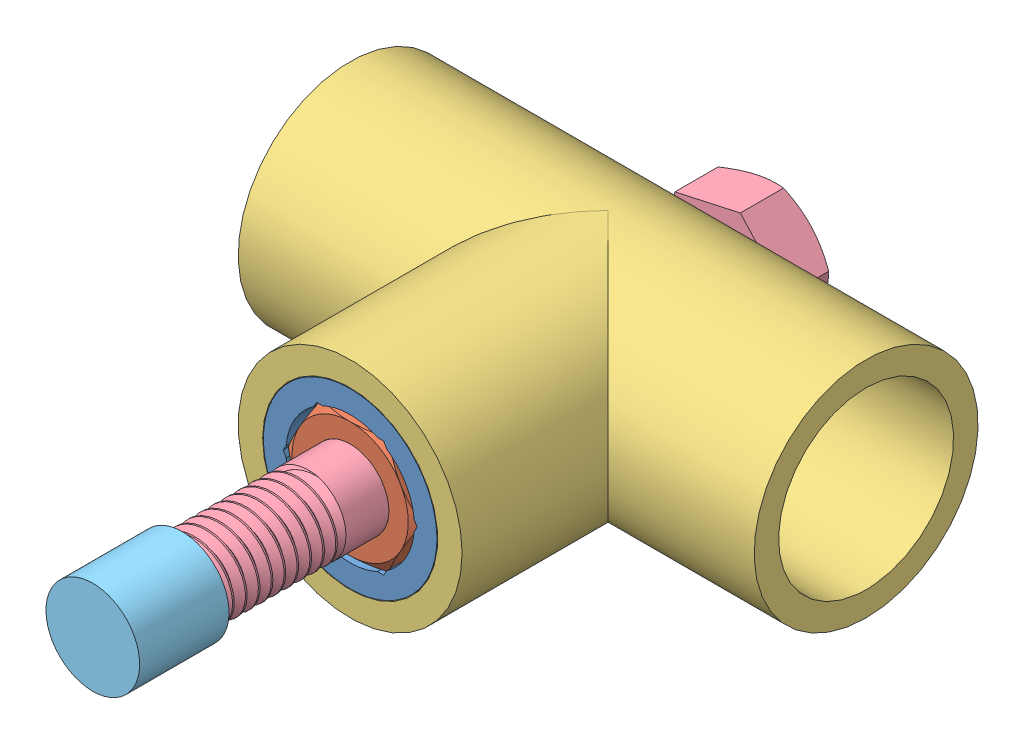
SolidWorks assembly BOLT, configuration Default. Lengths in mm.
Overall size (63.5 27.56 83.15).
5 component instances, 5 part files, 9 mates.
Components (placement in the parent):
- 1-2 PVC PIPE 1CM-1: 1-2 PVC PIPE 1CM [48925K91] at (8.3282 6.912 19.0537) size (21.34 21.34 10)
- 3-8 NUT-1: 3-8 NUT [94804A320] at (8.3282 6.912 19.8865) x (-0.866025 0.5 0) z (0 0 1) size (14.29 16.5 10.6)
- BOLT TEE-1: BOLT TEE [4880K41] at (8.3282 6.912 -7.6963) x (1 0 0) z (0 -1 0) size (63.5 45.53 27.56)
- 3-8 HEX HEAD CAP SCREW-1: 3-8 HEX HEAD CAP SCREW [92186A636] at (8.3282 6.912 13.6476) x (0 0 1) z (-0.95338 0.301772 0) size (82.75 16.5 14.29)
- VELCRO E-1: VELCRO E [Default] at (8.3282 6.912 55.7242) x (1 0 0) z (0 1 0) size (11.53 11 11.53)
Mates (geometry in assembly coordinates):
- Coincident1: coincident anti-aligned: plane of 1-2 PVC PIPE 1CM-1 through (0.0793 6.912 14.0537) normal (0.866025 0.5 0); plane of 3-8 NUT-1 through (0.0793 6.912 24.0537) normal (-0.866025 -0.5 0)
- Concentric1: concentric aligned: circle of 1-2 PVC PIPE 1CM-1; circle of 3-8 NUT-1
- Coincident2: coincident aligned: plane of 1-2 PVC PIPE 1CM-1 through (8.3282 6.912 24.0537) normal (0 0 1); plane of 3-8 NUT-1 through (12.4526 -0.2318 24.0537) normal (0 0 1)
- Concentric2: concentric aligned: cylinder of 1-2 PVC PIPE 1CM-1 through (8.3282 6.912 24.0537) axis (0 0 -1) radius 10.668; cone of BOLT TEE-1 through (8.3282 6.912 24.0537) axis (0 0 -1)
- Coincident3: coincident aligned: plane of 1-2 PVC PIPE 1CM-1 through (8.3282 6.912 24.0537) normal (0 0 1); plane of BOLT TEE-1 through (22.1077 6.912 24.0537) normal (0 0 1)
- Concentric3: concentric anti-aligned: cone of BOLT TEE-1 through (8.3282 6.912 24.0537) axis (0 0 -1); cylinder of 3-8 HEX HEAD CAP SCREW-1 through (8.3282 6.912 -21.4758) axis (0 0 1) radius 4.7625
- Tangent1: tangent anti-aligned: cylinder of BOLT TEE-1 through (21.0282 6.912 -7.6963) axis (-1 0 0) radius 13.7795; plane of 3-8 HEX HEAD CAP SCREW-1 through (2.7621 12.9999 -21.4758) normal (0 0 1)
- Coincident4: coincident anti-aligned: plane of 3-8 HEX HEAD CAP SCREW-1 through (8.3282 6.912 54.7242) normal (0 0 1); plane of VELCRO E-1 through (8.3282 6.912 54.7242) normal (0 0 -1)
- Concentric4: concentric aligned: cylinder of 3-8 HEX HEAD CAP SCREW-1 through (8.3282 6.912 -21.4758) axis (0 0 1) radius 4.7625; cylinder of VELCRO E-1 through (8.3282 6.912 54.7242) axis (0 0 1) radius 5.7625
